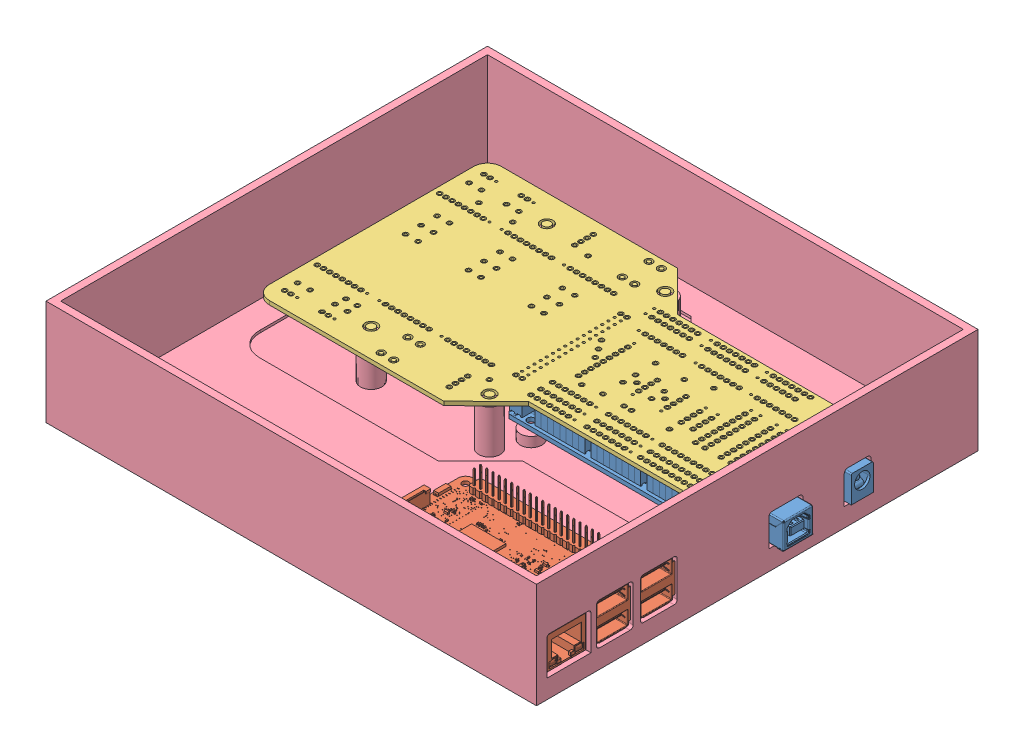
SolidWorks assembly Electronics_support_v1.1, configuration Valor predeterminado. Lengths in mm.
Overall size (205.51 43 180.38).
4 component instances, 4 part files, 6 mates.
Components (placement in the parent):
- Arduino Mega 2560-1: Arduino Mega 2560 [Default] at origin size (109.91 15.26 53.6)
- RaspberryPi 3-1: RaspberryPi 3 [Detailed] at (7.575 0.33 84.8) x (1 0 0) z (0 1 0) size (87.05 58.5 19.05)
- Crawler_PCB-1: Crawler_PCB [Default] at (44.9768 12.67 25.2213) x (-0.999987 0 0.005076) z (0 1 0) size (176.15 95.16 1.6)
- Electronics_case-1: Electronics_case [Valor predeterminado] at origin size (200.4 43 180.38)
Mates (geometry in assembly coordinates):
- Coincident1: coincident aligned: plane of Arduino Mega 2560-1 through (0 1.63 0) normal (0 1 0); plane of RaspberryPi 3-1 through (7.575 1.63 84.8) normal (0 1 0)
- Coincident2: coincident aligned: plane of Arduino Mega 2560-1 through (50.075 1.63 26.8) normal (1 0 0); plane of RaspberryPi 3-1 through (50.075 1.63 56.8) normal (1 0 0)
- Distance1: distance = 2.54 mm anti-aligned: plane of Crawler_PCB-1 through (-123.7475 12.67 42.6326) normal (0 -1 0); plane of Arduino Mega 2560-1 through (17.805 10.13 22.96) normal (0 1 0)
- Coincident4: coincident aligned: plane of Arduino Mega 2560-1 through (0 0 0) normal (0 0 1); plane of Crawler_PCB-1 through (44.9768 12.67 0) normal (0 0 1)
- Distance2: distance = 3.6 mm aligned: plane of Arduino Mega 2560-1 through (50.075 1.63 26.8) normal (1 0 0); plane of Crawler_PCB-1 through (46.475 14.27 24.8093) normal (1 0 0)
- Distance3: distance = 30 mm anti-aligned: plane of Arduino Mega 2560-1 through (-47.225 1.63 26.8) normal (0 0 1); plane of RaspberryPi 3-1 through (-34.925 1.63 56.8) normal (0 0 -1)
